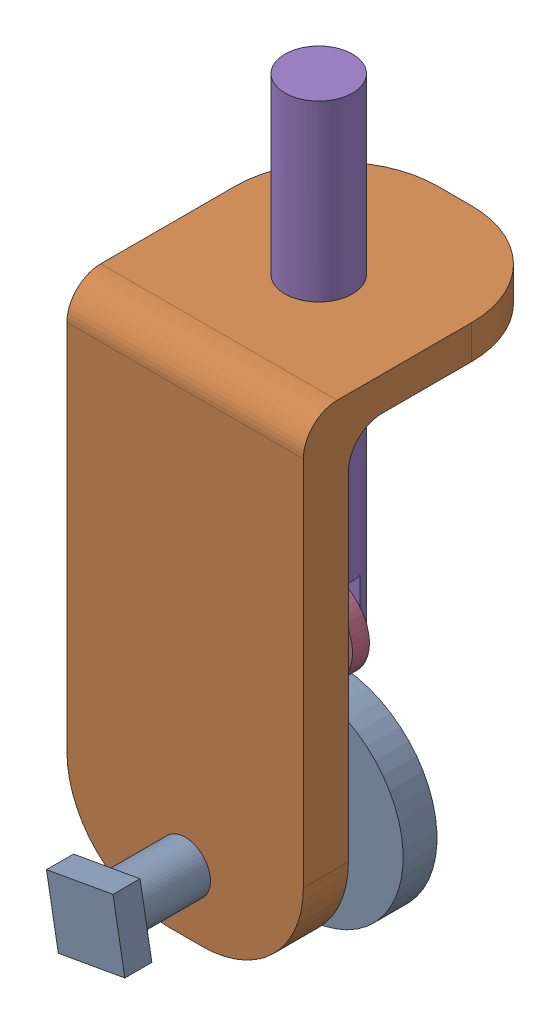
SolidWorks assembly CamAssembly, configuration Default. Lengths in mm.
Overall size (104.26 224.44 109.23).
6 component instances, 5 part files, 4 mates.
Components (placement in the parent):
- CAM-1: CAM [Default] at (-115.0914 93.3668 16.854) x (0.175462 -0.984486 0) z (0 0 1) size (60 95 74)
- Plate-1: Plate [Default] at (-65.8671 23.9222 19.354) size (70 150 79.79)
- ShaftAssembly-1: ShaftAssembly [Default] at (-65.689 137.0659 13.8703) size (32.26 157.13 20)
  - PIN-1: PIN [Default] at (-0.1781 -84.926 5.4837) size (10 10 14)
  - ROLLER-1: ROLLER [Default] at (32.7107 94.0296 5.4837) x (-0.934655 0.355555 0) z (0 0 1) size (25 25 5)
  - SHAFT-1: SHAFT [Default] at (-0.1781 -84.926 5.4837) size (20 149.68 20)
Mates (geometry in assembly coordinates):
- Concentric1: concentric anti-aligned: cylinder of CAM-1 through (-65.8671 102.1399 82.854) axis (0 0 -1) radius 7.5; cylinder of Plate-1 through (-65.8671 102.1399 -18.378) axis (0 0 1) radius 7.5
- Concentric2: concentric aligned: cylinder of Plate-1 through (-65.8671 199.1399 21.854) axis (0 1 0) radius 10; cylinder of ShaftAssembly-1/SHAFT-1 through (-65.8671 285.6399 21.854) axis (0 1 0) radius 10
- Width1: width aligned: plane of CAM-1 through (-65.8671 102.1399 16.854) normal (0 0 -1); plane of ShaftAssembly-1/ROLLER-1 through (-65.8671 102.1399 26.854) normal (0 0 1); plane of CAM-1 through (-65.8671 144.6399 19.354) normal (0 0 -1); plane of ShaftAssembly-1/ROLLER-1 through (-65.8671 144.6399 24.354) normal (0 0 1)
- CamMateTangent2: cam tangent anti-aligned: cylinder of CAM-1 through (-65.8671 102.1399 26.854) axis (0 0 -1) radius 30; cylinder of ShaftAssembly-1/ROLLER-1 through (-65.8671 144.6399 24.354) axis (0 0 -1) radius 12.5
